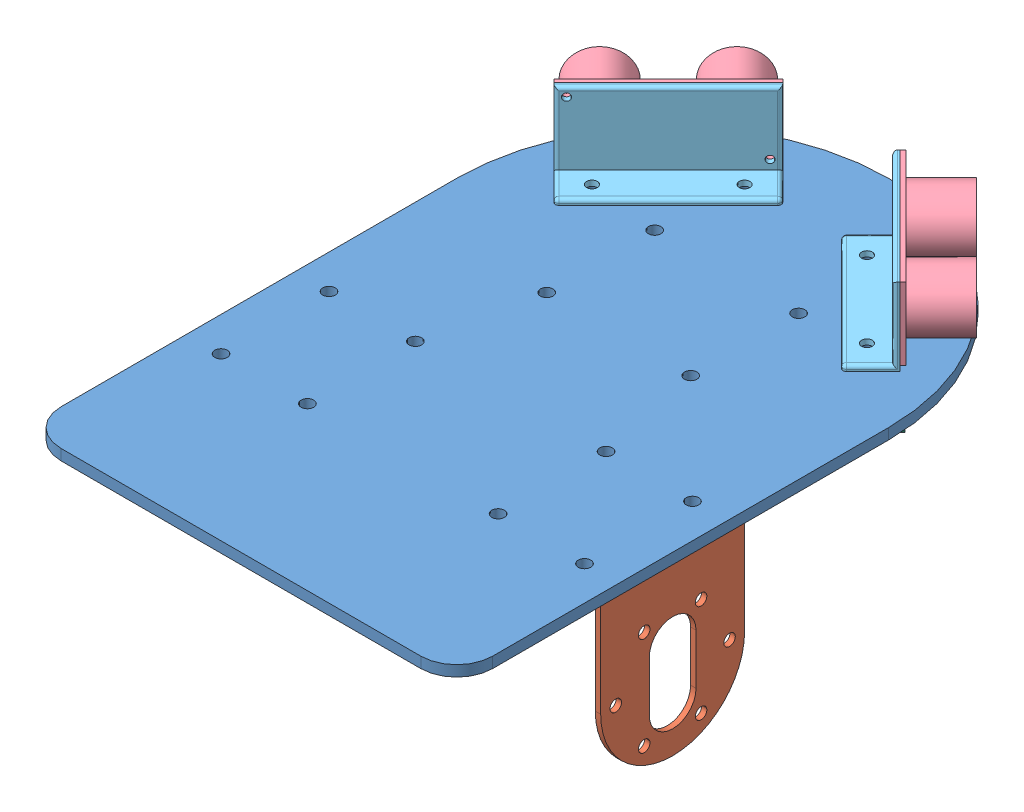
SolidWorks assembly Vehicle, configuration Default. Lengths in mm.
Overall size (120 70.5 180).
10 component instances, 6 part files, 14 mates.
Components (placement in the parent):
- Base-1: Base [Default] at origin size (120 3 180)
- Motor holder-2: Motor holder [Default] at (38.5 0 0) x (0 0 -1) z (-1 0 0) size (40 46 41.5)
- Motor holder-3: Motor holder [Default] at (-38.5 0 0) x (0 0 1) z (1 0 0) size (40 46 41.5)
- Omnidirectional wheel holder-1: Omnidirectional wheel holder [Default] at (0 -30.5 -60) size (50 30.5 40)
- Ultrasound sensor-2: Ultrasound sensor [Default] at (-32.2028 14.5 -90.9896) x (-0.707107 0 0.707107) z (-0.707107 0 -0.707107) size (45 20 15)
- Ultrasound sensor holder-1: Ultrasound sensor holder [Default] at (-31.1421 14.5 -89.9289) x (-0.707107 0 0.707107) z (-0.707107 0 -0.707107) size (45 21.5 11.5)
- Ultrasound sensor-3: Ultrasound sensor [Default] at (32.2028 14.5 -90.9896) x (-0.707107 0 -0.707107) z (0.707107 0 -0.707107) size (45 20 15)
- Ultrasound sensor holder-2: Ultrasound sensor holder [Default] at (31.1421 14.5 -89.9289) x (-0.707107 0 -0.707107) z (0.707107 0 -0.707107) size (45 21.5 11.5)
- Light sensor holder-1: Light sensor holder [Default] at (-31.8492 -9.05 -90.636) x (0.707107 0 -0.707107) z (-0.707107 0 -0.707107) size (40 16.6 13.5)
- Light sensor holder-2: Light sensor holder [Default] at (31.8492 -9.05 -90.636) x (0.707107 0 0.707107) z (0.707107 0 -0.707107) size (40 16.6 13.5)
Mates (geometry in assembly coordinates):
- Coincident3: coincident anti-aligned: plane of Base-1 through (0 0 -60) normal (0 -1 0); plane of Motor holder-2 through (38.5 0 0) normal (0 1 0)
- Coincident4: coincident anti-aligned: circle of Base-1; circle of Motor holder-2
- Coincident5: coincident anti-aligned: circle of Base-1; circle of Motor holder-2
- Coincident6: coincident anti-aligned: plane of Base-1 through (0 0 -60) normal (0 -1 0); plane of Omnidirectional wheel holder-1 through (13.5 0 -80) normal (0 1 0)
- Coincident7: coincident aligned: circle of Base-1; circle of Omnidirectional wheel holder-1
- Coincident8: coincident aligned: circle of Base-1; circle of Omnidirectional wheel holder-1
- Coincident13: coincident anti-aligned: plane of Base-1 through (0 3 -60) normal (0 1 0); plane of Ultrasound sensor holder-1 through (-31.1421 3 -89.9289) normal (0 -1 0)
- Coincident14: coincident anti-aligned: circle of Base-1; circle of Ultrasound sensor holder-1
- Coincident15: coincident anti-aligned: circle of Base-1; circle of Ultrasound sensor holder-1
- Coincident20: coincident aligned: circle of Ultrasound sensor-2; circle of Ultrasound sensor holder-1
- Coincident21: coincident aligned: circle of Ultrasound sensor-2; circle of Ultrasound sensor holder-1
- Coincident22: coincident anti-aligned: plane of Base-1 through (0 0 -60) normal (0 -1 0); plane of Light sensor holder-1 through (-31.8492 0 -90.636) normal (0 1 0)
- Coincident23: coincident anti-aligned: circle of Base-1; circle of Light sensor holder-1
- Coincident24: coincident anti-aligned: circle of Base-1; circle of Light sensor holder-1
